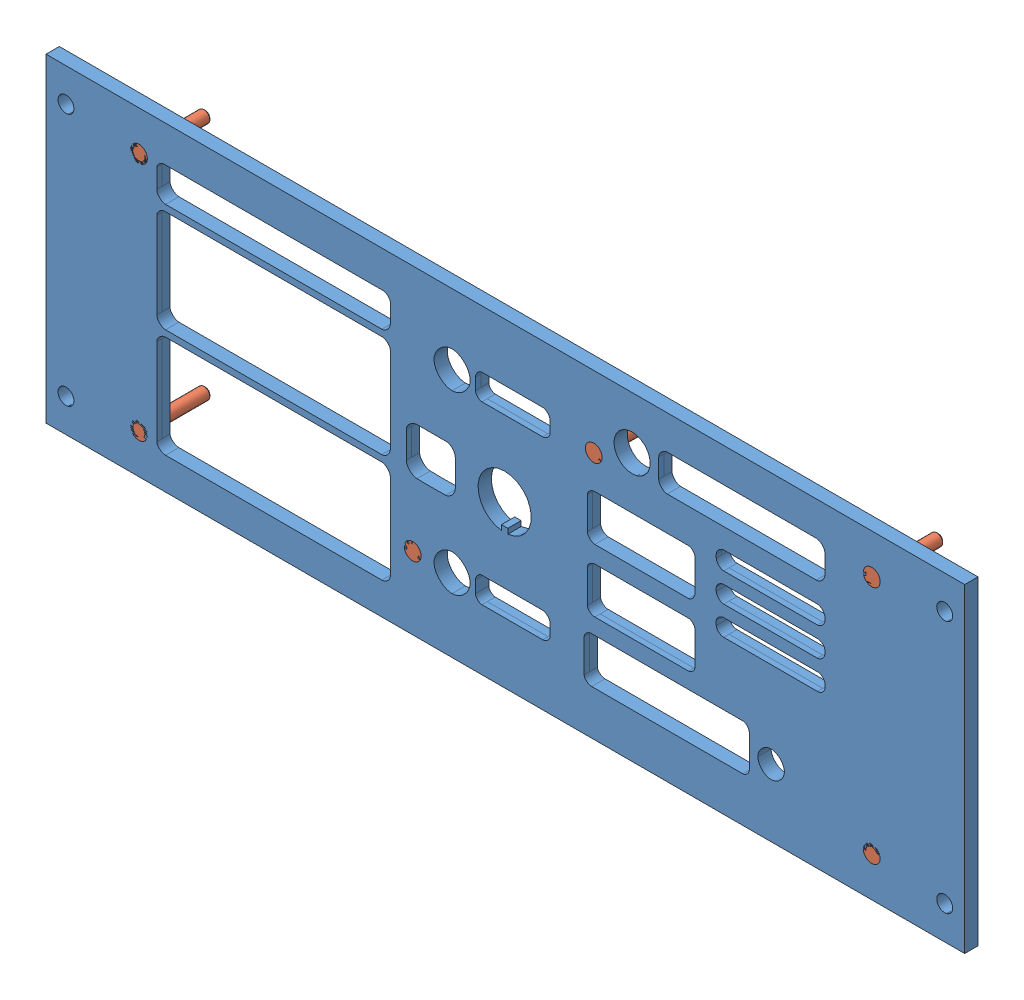
SolidWorks assembly 3009135_ASM_1, configuration Default. Lengths in mm.
Overall size (219.07 76.2 15.88).
7 component instances, 2 part files, 19 mates.
Components (placement in the parent):
- 3009135-1: 3009135 [Default] at origin size (219.07 76.2 3.18)
- 4050902_1-1: 4050902_1 [Default] at (87.376 28.575 3.175) x (0 0 -1) z (-1 0 0) size (15.88 4.47 4.47)
- 4050902_1-7: 4050902_1 [Default] at (87.376 -28.575 3.175) x (0 0 -1) z (-1 0 0) size (15.88 4.47 4.47)
- 4050902_1-8: 4050902_1 [Default] at (21.082 21.082 3.175) x (0 0 -1) z (-1 0 0) size (15.88 4.47 4.47)
- 4050902_1-9: 4050902_1 [Default] at (-22.098 -20.828 3.175) x (0 0 -1) z (-1 0 0) size (15.88 4.47 4.47)
- 4050902_1-10: 4050902_1 [Default] at (-87.376 28.575 3.175) x (0 0 -1) z (-1 0 0) size (15.88 4.47 4.47)
- 4050902_1-11: 4050902_1 [Default] at (-87.376 -28.575 3.175) x (0 0 -1) z (-1 0 0) size (15.88 4.47 4.47)
Mates (geometry in assembly coordinates):
- Coincident1: coordinate: point of 3009135-1
- Concentric1: concentric aligned: cylinder of 3009135-1 through (87.376 28.575 0) axis (0 0 1) radius 1.4097; cylinder of 4050902_1-1 through (87.376 28.575 -4.7968) axis (0 0 1) radius 1.4224
- Coincident3: coincident aligned: plane of 3009135-1 through (0 0 3.175) normal (0 0 1); plane of 4050902_1-1 through (86.3702 28.575 3.175) normal (0 0 1)
- Parallel2: parallel anti-aligned: plane of 3009135-1 through (0 0 0) normal (0 1 0); plane of 4050902_1-1 through (87.376 28.575 3.175) normal (0 -1 0)
- Coincident4: coincident aligned: plane of 3009135-1 through (0 0 3.175) normal (0 0 1); plane of 4050902_1-7 through (86.3702 -28.575 3.175) normal (0 0 1)
- Parallel3: parallel anti-aligned: plane of 3009135-1 through (0 0 0) normal (0 1 0); plane of 4050902_1-7 through (87.376 -28.575 3.175) normal (0 -1 0)
- Concentric2: concentric aligned: cylinder of 3009135-1 through (87.376 -28.575 0) axis (0 0 1) radius 1.4097; cylinder of 4050902_1-7 through (87.376 -28.575 -4.7968) axis (0 0 1) radius 1.4224
- Coincident5: coincident aligned: plane of 3009135-1 through (0 0 3.175) normal (0 0 1); plane of 4050902_1-8 through (20.0762 21.082 3.175) normal (0 0 1)
- Parallel4: parallel anti-aligned: plane of 3009135-1 through (0 0 0) normal (0 1 0); plane of 4050902_1-8 through (21.082 21.082 3.175) normal (0 -1 0)
- Concentric3: concentric aligned: cylinder of 3009135-1 through (21.082 21.082 0) axis (0 0 1) radius 1.4097; cylinder of 4050902_1-8 through (21.082 21.082 -4.7968) axis (0 0 1) radius 1.4224
- Coincident6: coincident aligned: plane of 3009135-1 through (0 0 3.175) normal (0 0 1); plane of 4050902_1-9 through (-23.1038 -20.828 3.175) normal (0 0 1)
- Parallel5: parallel anti-aligned: plane of 3009135-1 through (0 0 0) normal (0 1 0); plane of 4050902_1-9 through (-22.098 -20.828 3.175) normal (0 -1 0)
- Concentric4: concentric aligned: cylinder of 3009135-1 through (-22.098 -20.828 0) axis (0 0 1) radius 1.4097; cylinder of 4050902_1-9 through (-22.098 -20.828 -4.7968) axis (0 0 1) radius 1.4224
- Coincident7: coincident aligned: plane of 3009135-1 through (0 0 3.175) normal (0 0 1); plane of 4050902_1-10 through (-88.3818 28.575 3.175) normal (0 0 1)
- Parallel6: parallel anti-aligned: plane of 3009135-1 through (0 0 0) normal (0 1 0); plane of 4050902_1-10 through (-87.376 28.575 3.175) normal (0 -1 0)
- Concentric5: concentric aligned: cylinder of 3009135-1 through (-87.376 28.575 0) axis (0 0 1) radius 1.4097; cylinder of 4050902_1-10 through (-87.376 28.575 -4.7968) axis (0 0 1) radius 1.4224
- Coincident8: coincident aligned: plane of 3009135-1 through (0 0 3.175) normal (0 0 1); plane of 4050902_1-11 through (-88.3818 -28.575 3.175) normal (0 0 1)
- Parallel7: parallel anti-aligned: plane of 3009135-1 through (0 0 0) normal (0 1 0); plane of 4050902_1-11 through (-87.376 -28.575 3.175) normal (0 -1 0)
- Concentric6: concentric aligned: cylinder of 3009135-1 through (-87.376 -28.575 0) axis (0 0 1) radius 1.4097; cylinder of 4050902_1-11 through (-87.376 -28.575 -4.7968) axis (0 0 1) radius 1.4224
